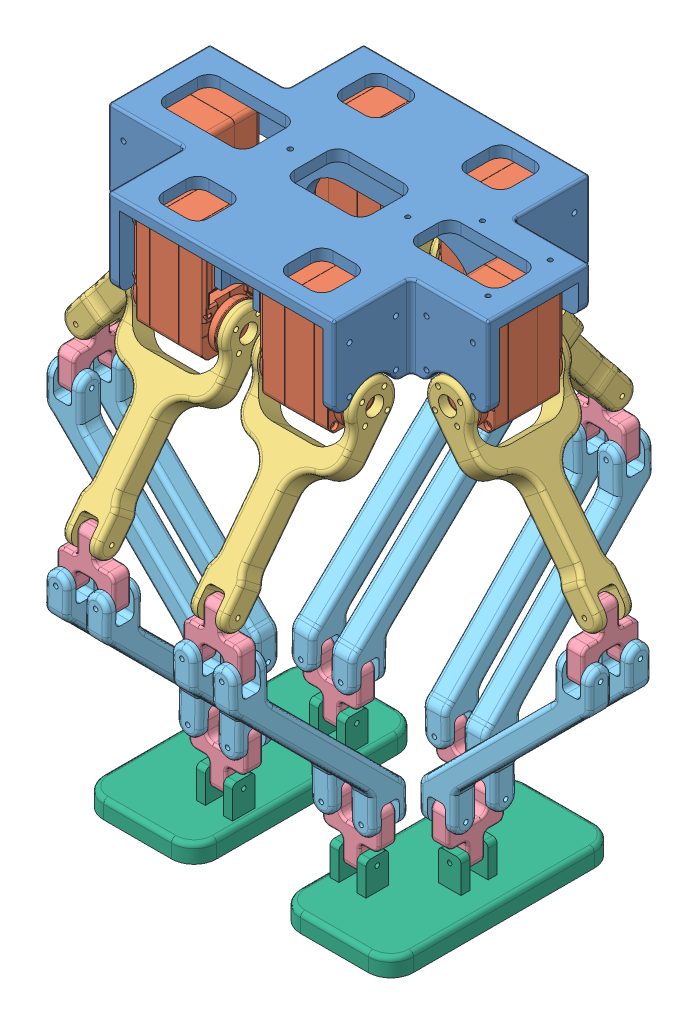
SolidWorks assembly bluefeet-urdf, configuration Default. Lengths in mm.
Overall size (254.56 248.23 199.52).
42 component instances, 6 part files, 75 mates.
Components (placement in the parent):
- link0-1: link0 [Default] x (1 0 0) z (0 0 -1) size (168 59.68 113)
  - platform-v4-1: platform-v4 [Default] at (0 36.8 -17.5) x (-1 0 0) z (0 0 1) size (168 36.8 113)
  - Servo-LX-16A-1: Servo-LX-16A [Default] at (37.5 14.825 39.5) x (0 -1 0) z (0 0 1) size (54.66 37.3 26.46)
  - Servo-LX-16A-2: Servo-LX-16A [Default] at (-37.5 14.825 39.5) x (0 -1 0) z (0 0 -1) size (54.66 37.3 26.46)
  - Servo-LX-16A-3: Servo-LX-16A [Default] at (-67 14.825 -10) x (0 -1 0) z (1 0 0) size (54.66 37.3 26.46)
  - Servo-LX-16A-4: Servo-LX-16A [Default] at (-37.5 14.825 -39.5) x (0 -1 0) z (0 0 -1) size (54.66 37.3 26.46)
  - Servo-LX-16A-5: Servo-LX-16A [Default] at (37.5 14.825 -39.5) x (0 -1 0) z (0 0 1) size (54.66 37.3 26.46)
  - Servo-LX-16A-6: Servo-LX-16A [Default] at (67 14.825 -10) x (0 -1 0) z (1 0 0) size (54.66 37.3 26.46)
- link1-1: link1 [Default] at (27.9 -74.503 60.6628) x (0 0.793607 -0.60843) z (1 0 0) size (96 20 46.12)
- link1-2: link1 [Default] at (88.1738 -74.4962 0.4) x (-0.608687 0.793411 0) z (0 0 -1) size (96 20 46.12)
- link1-3: link1 [Default] at (27.9 -74.503 -60.6628) x (0 0.793607 0.60843) z (-1 0 0) size (96 20 46.12)
- link1-4: link1 [Default] at (-27.9 -74.503 -60.6628) x (0 0.793607 0.60843) z (-1 0 0) size (96 20 46.12)
- link1-5: link1 [Default] at (-88.1738 -74.4962 0.4) x (0.608687 0.793411 0) z (0 0 1) size (96 20 46.12)
- link1-6: link1 [Default] at (-27.9 -74.503 60.6628) x (0 0.793607 -0.60843) z (1 0 0) size (96 20 46.12)
- link2-1: link2 [Default] at (27.9 -108.2473 85) x (1 0 0) z (0 0 -1) size (25.2 28 7.6)
- link2-2: link2 [Default] at (112.5213 -108.2326 0.4) x (0 0 1) z (1 0 0) size (25.2 28 7.6)
- link2-3: link2 [Default] at (27.9 -108.2473 -85) x (1 0 0) z (0 0 -1) size (25.2 28 7.6)
- link2-4: link2 [Default] at (-27.9 -108.2473 -85) x (1 0 0) z (0 0 -1) size (25.2 28 7.6)
- link2-5: link2 [Default] at (-112.5213 -108.2326 0.4) x (0 0 -1) z (-1 0 0) size (25.2 28 7.6)
- link2-6: link2 [Default] at (-27.9 -108.2473 85) x (1 0 0) z (0 0 -1) size (25.2 28 7.6)
- link3-1: link3 [Default] at (14.9116 -168.336 55) x (0 0 -1) z (0.999814 0.019301 0) size (76 94 10)
- link3-2: link3 [Default] at (32.5116 -168.336 55) x (0 0 1) z (0.999814 0.019301 0) size (76 94 10)
- link3-3: link3 [Default] at (82.5213 -168.2559 13.9999) x (-1 0 0) z (0 0.004762 -0.999989) size (76 94 10)
- link3-4: link3 [Default] at (82.5213 -168.2559 -3.6001) x (1 0 0) z (0 0.004762 -0.999989) size (76 94 10)
- link3-5: link3 [Default] at (42.5097 -168.143 -55) x (0 0 -1) z (-0.999814 -0.019301 0) size (76 94 10)
- link3-6: link3 [Default] at (24.9097 -168.143 -55) x (0 0 -1) z (-0.999814 -0.019301 0) size (76 94 10)
- link3-7: link3 [Default] at (-14.9116 -168.336 -55) x (0 0 1) z (-0.999814 0.019301 0) size (76 94 10)
- link3-8: link3 [Default] at (-32.5116 -168.336 -55) x (0 0 1) z (-0.999814 0.019301 0) size (76 94 10)
- link3-9: link3 [Default] at (-82.5213 -168.2083 -13.5999) x (1 0 0) z (0 -0.004762 0.999989) size (76 94 10)
- link3-10: link3 [Default] at (-82.5213 -168.2083 4.0001) x (1 0 0) z (0 -0.004762 0.999989) size (76 94 10)
- link3-11: link3 [Default] at (-42.5097 -168.143 55) x (0 0 -1) z (0.999814 -0.019301 0) size (76 94 10)
- link3-12: link3 [Default] at (-24.9097 -168.143 55) x (0 0 -1) z (0.999814 -0.019301 0) size (76 94 10)
- bluefeet-1: bluefeet [Default] at (43.5213 -248.2317 0) x (0 0 -1) z (1 0 0) size (100 41.94 54.92) (flexible)
  - feet-1: feet [Default] at origin size (100 22 50)
  - link2-1: link2 [Default] at (-25 20 -14) x (0 0 -1) z (1 0 0) size (25.2 28 7.6)
  - link2-2: link2 [Default] at (0 20 9) size (25.2 28 7.6)
  - link2-3: link2 [Default] at (25 20 -14) x (0 0 -1) z (1 0 0) size (25.2 28 7.6)
- bluefeet-2: bluefeet [Default] at (-43.5213 -248.2317 0) x (0 0 1) z (-1 0 0) size (100 41.94 54.92) (flexible)
  - feet-1: feet [Default] at origin size (100 22 50)
  - link2-1: link2 [Default] at (-25 20 -14) x (0 0 -1) z (1 0 0) size (25.2 28 7.6)
  - link2-2: link2 [Default] at (0 20 9) size (25.2 28 7.6)
  - link2-3: link2 [Default] at (25 20 -14) x (0 0 -1) z (1 0 0) size (25.2 28 7.6)
Mates (geometry in assembly coordinates):
- Coincident1: coincident aligned: plane of link0-1/platform-v4-1 through (0 0 17.5) normal (0 1 0)
- Coincident2: coincident anti-aligned: plane of link0-1/platform-v4-1 through (0 -36.8 17.5) normal (-1 0 0)
- Coincident4: coincident anti-aligned: plane of link0-1/platform-v4-1 through (0 -36.8 0) normal (0 0 -1)
- Concentric1: concentric aligned: cylinder of link0-1/Servo-LX-16A-5 through (46.6 -40.325 39.5) axis (1 0 0) radius 10; cylinder of link1-1 through (4.9 -40.325 39.5) axis (1 0 0) radius 4
- Distance1: distance = 0.9 mm anti-aligned: plane of link0-1/Servo-LX-16A-5 through (46 -29.3267 39.5) normal (1 0 0); plane of link1-1 through (46.9 -60.5091 78.9158) normal (-1 0 0)
- Concentric2: concentric: cylinder of link0-1/Servo-LX-16A-6 through (67 -40.325 -14.6) axis (0 0 1) radius 10; cylinder of link1-2 through (67 -40.325 23.4) axis (0 0 -1) radius 4
- Distance2: distance = 0.9 mm: plane of link1-2 through (106.4223 -60.4964 -18.6) normal (0 0 1); plane of link0-1/Servo-LX-16A-6 through (86.9 -79.4276 -17.7) normal (0 0 -1)
- Concentric3: concentric anti-aligned: cylinder of link0-1/Servo-LX-16A-1 through (46.6 -40.325 -39.5) axis (1 0 0) radius 10; cylinder of link1-3 through (50.9 -40.325 -39.5) axis (-1 0 0) radius 4
- Distance3: distance = 0.9 mm anti-aligned: plane of link1-3 through (8.9 -60.5091 -78.9158) normal (1 0 0); plane of link0-1/Servo-LX-16A-1 through (9.8 -79.4276 -59.4) normal (-1 0 0)
- Concentric4: concentric aligned: cylinder of link0-1/Servo-LX-16A-2 through (-46.6 -40.325 -39.5) axis (-1 0 0) radius 10; cylinder of link1-4 through (-4.9 -40.325 -39.5) axis (-1 0 0) radius 4
- Distance4: distance = 0.9 mm anti-aligned: plane of link1-4 through (-8.9 -60.5091 -78.9158) normal (-1 0 0); plane of link0-1/Servo-LX-16A-2 through (-9.8 -79.4276 -19.6) normal (1 0 0)
- Concentric5: concentric aligned: cylinder of link0-1/Servo-LX-16A-3 through (-67 -40.325 19.1) axis (0 0 1) radius 10; cylinder of link1-5 through (-67 -40.325 -22.6) axis (0 0 1) radius 4
- Distance5: distance = 0.9 mm anti-aligned: plane of link1-5 through (-106.4223 -60.4964 -18.6) normal (0 0 1); plane of link0-1/Servo-LX-16A-3 through (-47.1 -79.4276 -17.7) normal (0 0 -1)
- Concentric6: concentric anti-aligned: cylinder of link1-6 through (-50.9 -40.325 39.5) axis (1 0 0) radius 4; cylinder of link0-1/Servo-LX-16A-4 through (-46.6 -40.325 39.5) axis (-1 0 0) radius 10
- Distance6: distance = 0.9 mm anti-aligned: plane of link1-6 through (-8.9 -60.5091 78.9158) normal (-1 0 0); plane of link0-1/Servo-LX-16A-4 through (-9.8 -79.4276 59.4) normal (1 0 0)
- Concentric7: concentric aligned: cylinder of link1-1 through (4.9 -106.2473 85) axis (1 0 0) radius 1; cylinder of link2-1 through (24.1 -106.2473 85) axis (1 0 0) radius 1.15
- Distance7: distance = 0.2 mm anti-aligned: plane of link2-1 through (31.7 -108.2473 88.8) normal (1 0 0); plane of link1-1 through (31.9 -60.5091 78.9158) normal (-1 0 0)
- Concentric8: concentric anti-aligned: cylinder of link1-2 through (112.5213 -106.2326 23.4) axis (0 0 -1) radius 1; cylinder of link2-2 through (112.5213 -106.2326 -3.4) axis (0 0 1) radius 1.15
- Distance8: distance = 0.2 mm anti-aligned: plane of link2-2 through (108.7213 -108.2326 -3.4) normal (0 0 -1); plane of link1-2 through (106.4223 -60.4964 -3.6) normal (0 0 1)
- Concentric9: concentric anti-aligned: cylinder of link1-3 through (50.9 -106.2473 -85) axis (-1 0 0) radius 1; cylinder of link2-3 through (24.1 -106.2473 -85) axis (1 0 0) radius 1.15
- Distance9: distance = 0.2 mm anti-aligned: plane of link2-3 through (31.7 -108.2473 -81.2) normal (1 0 0); plane of link1-3 through (31.9 -60.5091 -78.9158) normal (-1 0 0)
- Concentric10: concentric anti-aligned: cylinder of link1-4 through (-4.9 -106.2473 -85) axis (-1 0 0) radius 1; cylinder of link2-4 through (-31.7 -106.2473 -85) axis (1 0 0) radius 1.15
- Distance10: distance = 0.2 mm anti-aligned: plane of link2-4 through (-31.7 -108.2473 -81.2) normal (-1 0 0); plane of link1-4 through (-31.9 -60.5091 -78.9158) normal (1 0 0)
- Concentric11: concentric anti-aligned: cylinder of link1-5 through (-112.5213 -106.2326 -22.6) axis (0 0 1) radius 1; cylinder of link2-5 through (-112.5213 -106.2326 4.2) axis (0 0 -1) radius 1.15
- Distance11: distance = 0.2 mm anti-aligned: plane of link2-5 through (-108.7213 -108.2326 -3.4) normal (0 0 -1); plane of link1-5 through (-106.4223 -60.4964 -3.6) normal (0 0 1)
- Concentric12: concentric aligned: cylinder of link1-6 through (-50.9 -106.2473 85) axis (1 0 0) radius 1; cylinder of link2-6 through (-31.7 -106.2473 85) axis (1 0 0) radius 1.15
- Distance12: distance = 0.2 mm anti-aligned: plane of link2-6 through (-31.7 -108.2473 88.8) normal (-1 0 0); plane of link1-6 through (-31.9 -60.5091 78.9158) normal (1 0 0)
- Concentric13: concentric aligned: cylinder of link2-1 through (19.1 -126.2473 88.8) axis (0 0 -1) radius 1.15; cylinder of link3-1 through (19.1 -126.2473 93) axis (0 0 -1) radius 1
- Distance13: distance = 0.2 mm anti-aligned: plane of link3-1 through (24.9097 -168.143 89) normal (0 0 -1); plane of link2-1 through (27.9 -108.2473 88.8) normal (0 0 1)
- Concentric14: concentric anti-aligned: cylinder of link3-2 through (36.7 -126.2473 77) axis (0 0 1) radius 1; cylinder of link2-1 through (36.7 -126.2473 88.8) axis (0 0 -1) radius 1.15
- Distance14: distance = 0.2 mm anti-aligned: plane of link3-2 through (42.5097 -168.143 89) normal (0 0 -1); plane of link2-1 through (27.9 -108.2473 88.8) normal (0 0 1)
- Concentric15: concentric anti-aligned: cylinder of link2-2 through (108.7213 -126.2326 9.2) axis (1 0 0) radius 1.15; cylinder of link3-3 through (120.5213 -126.2326 9.2) axis (-1 0 0) radius 1
- Distance15: distance = 0.2 mm anti-aligned: plane of link3-3 through (116.5213 -168.2083 4.0001) normal (-1 0 0); plane of link2-2 through (116.3213 -108.2326 0.4) normal (1 0 0)
- Concentric16: concentric aligned: cylinder of link2-2 through (108.7213 -126.2326 -8.4) axis (1 0 0) radius 1.15; cylinder of link3-4 through (104.5213 -126.2326 -8.4) axis (1 0 0) radius 1
- Distance16: distance = 0.2 mm anti-aligned: plane of link3-4 through (116.5213 -168.2083 -13.5999) normal (-1 0 0); plane of link2-2 through (116.3213 -108.2326 0.4) normal (1 0 0)
- Concentric17: concentric aligned: cylinder of link3-6 through (19.1 -126.2473 -77) axis (0 0 -1) radius 1; cylinder of link2-3 through (19.1 -126.2473 -81.2) axis (0 0 -1) radius 1.15
- Distance17: distance = 0.2 mm anti-aligned: plane of link3-6 through (14.9116 -168.336 -89) normal (0 0 1); plane of link2-3 through (27.9 -108.2473 -88.8) normal (0 0 -1)
- Concentric18: concentric aligned: cylinder of link3-5 through (36.7 -126.2473 -77) axis (0 0 -1) radius 1; cylinder of link2-3 through (36.7 -126.2473 -81.2) axis (0 0 -1) radius 1.15
- Distance18: distance = 0.2 mm anti-aligned: plane of link3-5 through (32.5116 -168.336 -89) normal (0 0 1); plane of link2-3 through (27.9 -108.2473 -88.8) normal (0 0 -1)
- Concentric19: concentric anti-aligned: cylinder of link2-4 through (-19.1 -126.2473 -81.2) axis (0 0 -1) radius 1.15; cylinder of link3-7 through (-19.1 -126.2473 -93) axis (0 0 1) radius 1
- Distance19: distance = 0.2 mm anti-aligned: plane of link3-7 through (-24.9097 -168.143 -81) normal (0 0 -1); plane of link2-4 through (-27.9 -108.2473 -81.2) normal (0 0 1)
- Concentric20: concentric anti-aligned: cylinder of link2-4 through (-36.7 -126.2473 -81.2) axis (0 0 -1) radius 1.15; cylinder of link3-8 through (-36.7 -126.2473 -93) axis (0 0 1) radius 1
- Distance20: distance = 0.2 mm anti-aligned: plane of link3-8 through (-42.5097 -168.143 -81) normal (0 0 -1); plane of link2-4 through (-27.9 -108.2473 -81.2) normal (0 0 1)
- Concentric21: concentric anti-aligned: cylinder of link2-5 through (-108.7213 -126.2326 -8.4) axis (-1 0 0) radius 1.15; cylinder of link3-9 through (-120.5213 -126.2326 -8.4) axis (1 0 0) radius 1
- Distance21: distance = 0.2 mm anti-aligned: plane of link3-9 through (-108.5213 -168.2559 -3.6001) normal (-1 0 0); plane of link2-5 through (-108.7213 -108.2326 0.4) normal (1 0 0)
- Concentric22: concentric anti-aligned: cylinder of link2-5 through (-108.7213 -126.2326 9.2) axis (-1 0 0) radius 1.15; cylinder of link3-10 through (-120.5213 -126.2326 9.2) axis (1 0 0) radius 1
- Distance22: distance = 0.2 mm anti-aligned: plane of link3-10 through (-108.5213 -168.2559 13.9999) normal (-1 0 0); plane of link2-5 through (-108.7213 -108.2326 0.4) normal (1 0 0)
- Concentric23: concentric aligned: cylinder of link2-6 through (-36.7 -126.2473 88.8) axis (0 0 -1) radius 1.15; cylinder of link3-11 through (-36.7 -126.2473 93) axis (0 0 -1) radius 1
- Distance23: distance = 0.2 mm anti-aligned: plane of link3-11 through (-32.5116 -168.336 81) normal (0 0 1); plane of link2-6 through (-27.9 -108.2473 81.2) normal (0 0 -1)
- Concentric24: concentric aligned: cylinder of link2-6 through (-19.1 -126.2473 88.8) axis (0 0 -1) radius 1.15; cylinder of link3-12 through (-19.1 -126.2473 93) axis (0 0 -1) radius 1
- Distance24: distance = 0.2 mm anti-aligned: plane of link3-12 through (-14.9116 -168.336 81) normal (0 0 1); plane of link2-6 through (-27.9 -108.2473 81.2) normal (0 0 -1)
- Concentric29: concentric aligned: cylinder of link3-4 through (44.5213 -210.2317 -8.8) axis (1 0 0) radius 1; cylinder of bluefeet-1/link2-2 through (48.7213 -210.2317 -8.8) axis (1 0 0) radius 1.15
- Distance26: distance = 0.2 mm anti-aligned: plane of bluefeet-1/link2-2 through (56.3213 -228.2317 0) normal (1 0 0); plane of link3-4 through (56.5213 -168.2083 -13.5999) normal (-1 0 0)
- Concentric30: concentric anti-aligned: cylinder of link3-3 through (60.5213 -210.2317 8.8) axis (-1 0 0) radius 1; cylinder of bluefeet-1/link2-2 through (48.7213 -210.2317 8.8) axis (1 0 0) radius 1.15
- Concentric31: concentric anti-aligned: cylinder of link3-2 through (38.3213 -210.2317 17) axis (0 0 1) radius 1; cylinder of bluefeet-1/link2-1 through (38.3213 -210.2317 28.8) axis (0 0 -1) radius 1.15
- Distance27: distance = 0.2 mm anti-aligned: plane of link3-2 through (42.5097 -168.143 29) normal (0 0 -1); plane of bluefeet-1/link2-1 through (29.5213 -228.2317 28.8) normal (0 0 1)
- Concentric32: concentric aligned: cylinder of link3-1 through (20.7213 -210.2317 33) axis (0 0 -1) radius 1; cylinder of bluefeet-1/link2-1 through (20.7213 -210.2317 28.8) axis (0 0 -1) radius 1.15
- Concentric33: concentric aligned: cylinder of link3-5 through (38.3213 -210.2317 -17) axis (0 0 -1) radius 1; cylinder of bluefeet-1/link2-3 through (38.3213 -210.2317 -21.2) axis (0 0 -1) radius 1.15
- Distance28: distance = 0.2 mm anti-aligned: plane of bluefeet-1/link2-3 through (29.5213 -228.2317 -28.8) normal (0 0 -1); plane of link3-5 through (32.5116 -168.336 -29) normal (0 0 1)
- Concentric34: concentric aligned: cylinder of link3-6 through (20.7213 -210.2317 -17) axis (0 0 -1) radius 1; cylinder of bluefeet-1/link2-3 through (20.7213 -210.2317 -21.2) axis (0 0 -1) radius 1.15
- Concentric35: concentric anti-aligned: cylinder of link3-9 through (-60.5213 -210.2317 -8.8) axis (1 0 0) radius 1; cylinder of bluefeet-2/link2-2 through (-48.7213 -210.2317 -8.8) axis (-1 0 0) radius 1.15
- Distance29: distance = 0.2 mm anti-aligned: plane of bluefeet-2/link2-2 through (-56.3213 -228.2317 0) normal (-1 0 0); plane of link3-9 through (-56.5213 -168.2559 -3.6001) normal (1 0 0)
- Concentric36: concentric anti-aligned: cylinder of link3-10 through (-60.5213 -210.2317 8.8) axis (1 0 0) radius 1; cylinder of bluefeet-2/link2-2 through (-48.7213 -210.2317 8.8) axis (-1 0 0) radius 1.15
- Concentric37: concentric aligned: cylinder of link3-8 through (-38.3213 -210.2317 -33) axis (0 0 1) radius 1; cylinder of bluefeet-2/link2-1 through (-38.3213 -210.2317 -28.8) axis (0 0 1) radius 1.15
- Distance30: distance = 0.2 mm anti-aligned: plane of bluefeet-2/link2-1 through (-29.5213 -228.2317 -28.8) normal (0 0 -1); plane of link3-8 through (-42.5097 -168.143 -29) normal (0 0 1)
- Concentric38: concentric aligned: cylinder of link3-7 through (-20.7213 -210.2317 -33) axis (0 0 1) radius 1; cylinder of bluefeet-2/link2-1 through (-20.7213 -210.2317 -28.8) axis (0 0 1) radius 1.15
- Concentric39: concentric anti-aligned: cylinder of link3-11 through (-38.3213 -210.2317 33) axis (0 0 -1) radius 1; cylinder of bluefeet-2/link2-3 through (-38.3213 -210.2317 21.2) axis (0 0 1) radius 1.15
- Distance31: distance = 0.2 mm anti-aligned: plane of link3-11 through (-32.5116 -168.336 29) normal (0 0 -1); plane of bluefeet-2/link2-3 through (-29.5213 -228.2317 28.8) normal (0 0 1)
- Concentric40: concentric anti-aligned: cylinder of link3-12 through (-20.7213 -210.2317 33) axis (0 0 -1) radius 1; cylinder of bluefeet-2/link2-3 through (-20.7213 -210.2317 21.2) axis (0 0 1) radius 1.15
- Parallel3: parallel aligned: plane of link0-1/platform-v4-1 through (84 -5 -17.5) normal (1 0 0); plane of link2-2 through (116.3213 -108.2326 0.4) normal (1 0 0)
- Parallel4: parallel aligned: plane of link0-1/platform-v4-1 through (-50 -5 -56.5) normal (0 0 -1); plane of link2-3 through (27.9 -108.2473 -88.8) normal (0 0 -1)
- Parallel5: parallel aligned: plane of link0-1/platform-v4-1 through (50 0 56.5) normal (0 0 1); plane of link2-1 through (27.9 -108.2473 88.8) normal (0 0 1)
- Parallel6: parallel aligned: plane of link0-1/platform-v4-1 through (-84 -5 -17.5) normal (-1 0 0); plane of link2-5 through (-116.3213 -108.2326 0.4) normal (-1 0 0)
- Parallel7: parallel aligned: plane of link0-1/platform-v4-1 through (-50 -5 -56.5) normal (0 0 -1); plane of link2-4 through (-27.9 -108.2473 -88.8) normal (0 0 -1)
- Parallel8: parallel aligned: plane of link2-6 through (-27.9 -108.2473 88.8) normal (0 0 1); plane of link0-1/platform-v4-1 through (50 0 56.5) normal (0 0 1)
